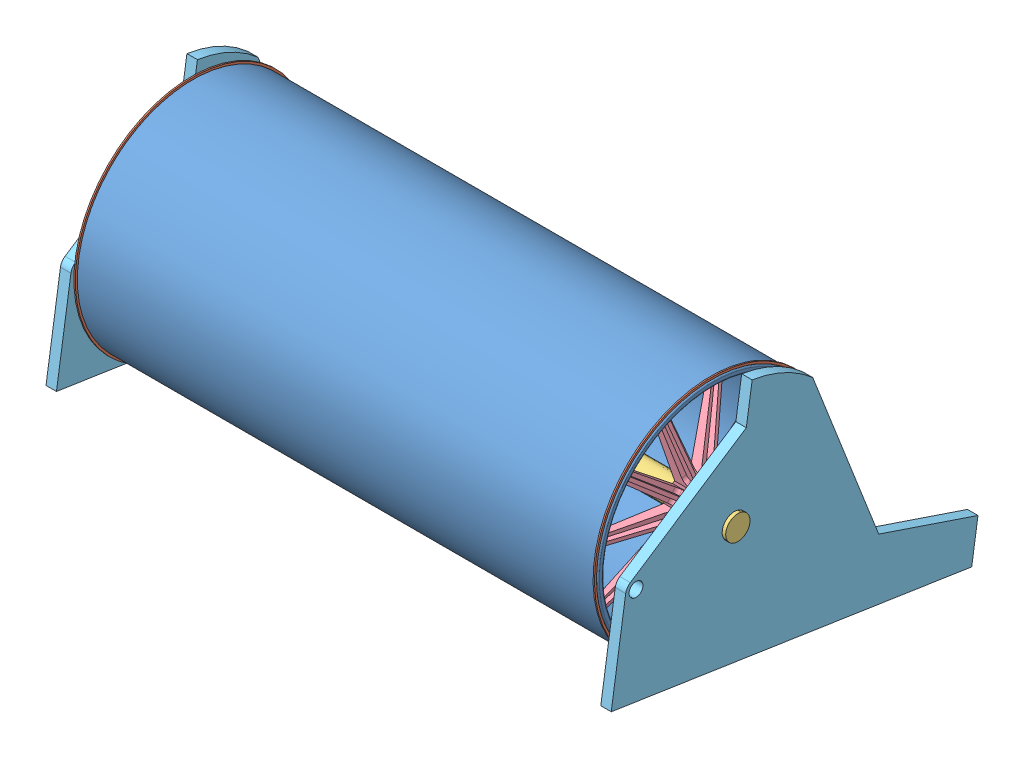
SolidWorks assembly Doffer assembly, configuration Default. Lengths in mm.
Overall size (875 441.45 610.99).
8 component instances, 5 part files, 12 mates.
Components (placement in the parent):
- Doffer Cylinder-1: Doffer Cylinder [Default] at (352.9425 14.4736 1.8063) x (1 0 0) z (0 0.42516 0.905118) size (750 331 331)
- Doffer Ring-2: Doffer Ring [Default] at (348.9425 14.4736 1.8063) x (1 0 0) z (0 -0.936355 0.351055) size (2 337 337)
- Doffer Ring-4: Doffer Ring [Default] at (-395.0575 14.4736 1.8063) x (1 0 0) z (0 0.92451 -0.381158) size (2 337 337)
- Doffer Shaft-1: Doffer Shaft [Default] at (-49.5575 14.4736 1.8063) x (1 0 0) z (0 -0.723885 -0.689921) size (875 35 35)
- support-1: support [Default] at (352.9425 14.4736 1.8063) x (0 0.529996 -0.848) z (-1 0 0) size (312.12 307.38 70.5)
- support-2: support [Default] at (-397.0575 14.4736 1.8063) x (0 -0.529996 0.848) z (1 0 0) size (312.12 307.38 70.5)
- Doffer_Frame-1: Doffer_Frame [Default] at (-427.0575 -128.4059 178.2467) x (0 -0.150072 -0.988675) z (1 0 0) size (522.5 337.74 15)
- Doffer_Frame-2: Doffer_Frame [Default] at (367.9425 -128.4059 178.2467) x (0 -0.150072 -0.988675) z (1 0 0) size (522.5 337.74 15)
Mates (geometry in assembly coordinates):
- Concentric8: concentric: circle of Doffer Cylinder-1; cylinder of Doffer Ring-2 through (350.9425 14.4736 1.8063) axis (-1 0 0) radius 165.5
- Concentric10: concentric: cylinder of Doffer Cylinder-1 through (-397.0575 14.4736 1.8063) axis (1 0 0) radius 157.5; cylinder of Doffer Ring-2 through (350.9425 14.4736 1.8063) axis (-1 0 0) radius 168.5
- Concentric11: concentric: cylinder of Doffer Cylinder-1 through (-397.0575 14.4736 1.8063) axis (1 0 0) radius 165.5; cylinder of Doffer Ring-2 through (350.9425 14.4736 1.8063) axis (-1 0 0) radius 168.5
- Tangent5: tangent: circle of Doffer Cylinder-1; cylinder of Doffer Ring-4 through (-393.0575 14.4736 1.8063) axis (-1 0 0) radius 165.5
- Concentric14: concentric: circle of Doffer Cylinder-1; cylinder of Doffer Ring-4 through (-393.0575 14.4736 1.8063) axis (-1 0 0) radius 168.5
- Coincident5: coincident: circle of Doffer Cylinder-1; circle of Doffer Ring-4
- Coincident6: coincident: circle of Doffer Cylinder-1; circle of Doffer Ring-2
- Concentric15: concentric: cylinder of Doffer Cylinder-1 through (-397.0575 14.4736 1.8063) axis (1 0 0) radius 157.5; cylinder of Doffer Shaft-1 through (387.9425 14.4736 1.8063) axis (-1 0 0) radius 17.5
- Distance1: distance = 90 mm: plane of Doffer Shaft-1 through (-487.0575 14.4736 1.8063) normal (-1 0 0); plane of Doffer Cylinder-1 through (-397.0575 14.4736 1.8063) normal (-1 0 0)
- Concentric16: concentric: cylinder of Doffer Shaft-1 through (387.9425 14.4736 1.8063) axis (-1 0 0) radius 17.5; cylinder of support-1 through (312.9425 14.4736 1.8063) axis (1 0 0) radius 17.5
- Concentric17: concentric: cylinder of Doffer Shaft-1 through (387.9425 14.4736 1.8063) axis (-1 0 0) radius 17.5; cylinder of Doffer_Frame-1 through (-412.0575 14.4736 1.8063) axis (-1 0 0) radius 17.5
- Coincident11: coincident: circle of Doffer Cylinder-1; plane of support-2 through (-397.0575 14.4736 1.8063) normal (-1 0 0)
